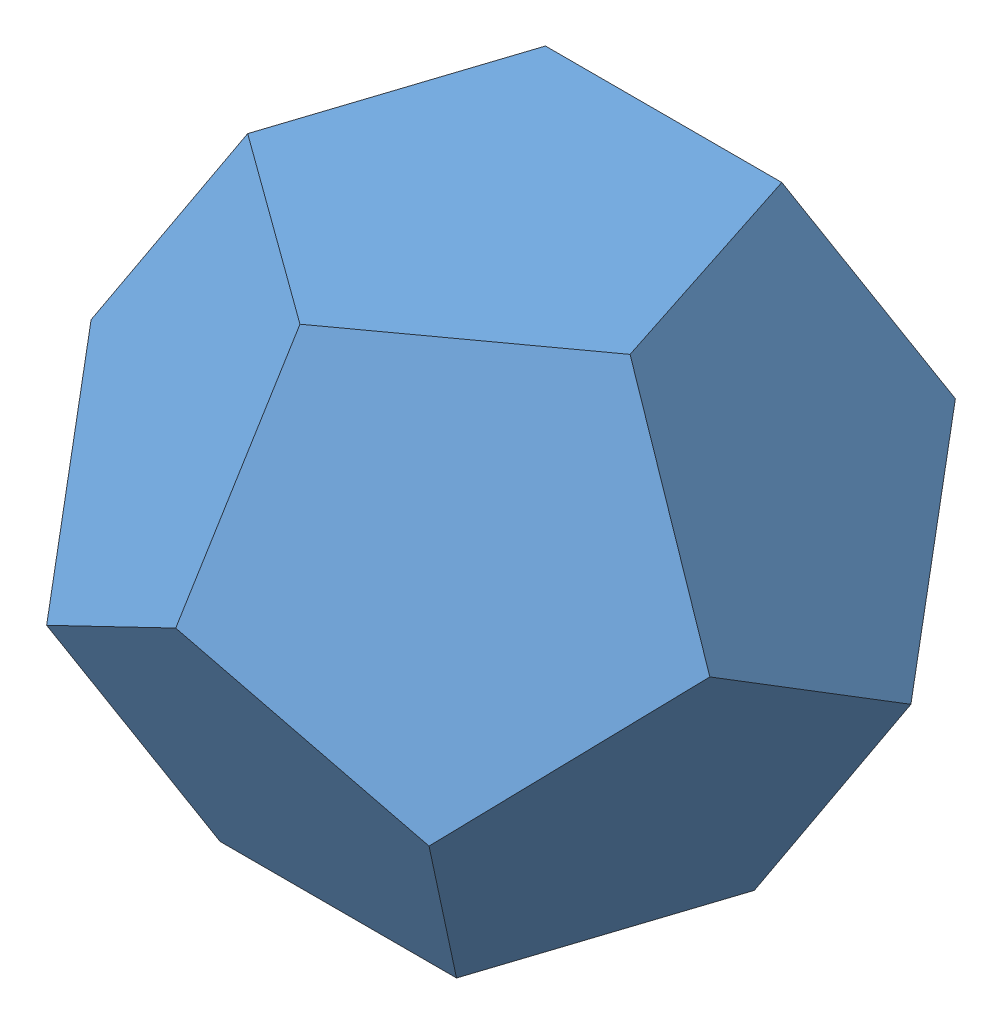
SolidWorks assembly Assem1, configuration Default. Lengths in mm.
Overall size (49.2 47.26 43.46).
6 component instances, 1 part files, 18 mates.
Components (placement in the parent):
- 2 Pyramid-1: 2 Pyramid [Default] at (0 -14.1417 0) size (26.9 17.48 24.94)
- 2 Pyramid-2: 2 Pyramid [Default] at (7.4347 -6.3243 -10.233) x (-0.5 0.525731 -0.688191) z (0.688191 0.723607 0.052786) size (26.9 17.48 24.94)
- 2 Pyramid-3: 2 Pyramid [Default] at (0 -6.3243 12.6487) x (-0.309017 0.850651 0.425325) z (-0.951057 -0.276393 -0.138197) size (26.9 17.48 24.94)
- 2 Pyramid-4: 2 Pyramid [Default] at (-12.0296 6.3243 -3.9087) x (0.309017 0.850651 0.425325) z (0.425325 0.276393 -0.861803) size (26.9 17.48 24.94)
- 2 Pyramid-5: 2 Pyramid [Default] at (-7.4347 -6.3243 -10.233) x (-0.5 -0.525731 0.688191) z (-0.688191 0.723607 0.052786) size (26.9 17.48 24.94)
- 2 Pyramid-6: 2 Pyramid [Default] at (7.4347 6.3243 10.233) x (0.809017 0 -0.587785) z (-0.262866 0.894427 -0.361803) size (26.9 17.48 24.94)
Mates (geometry in assembly coordinates):
- Coincident1: coincident: point of 2 Pyramid-1
- Parallel1: parallel aligned: plane of 2 Pyramid-1 through (0 -14.1417 0) normal (0 1 0)
- Coincident3: coincident aligned: plane of 2 Pyramid-1 through (0 -14.1417 0) normal (0 0 1)
- Coincident5: coincident anti-aligned: plane of 2 Pyramid-1 through (10.2745 -14.1417 -3.3384) normal (-0.309017 0 -0.951057); plane of 2 Pyramid-2 through (10.2745 -14.1417 -3.3384) normal (0.309017 0 0.951057)
- Coincident6: coincident anti-aligned: plane of 2 Pyramid-1 through (10.2745 -14.1417 -3.3384) normal (0.5 0.525731 -0.688191); plane of 2 Pyramid-2 through (0 -14.1417 -10.8033) normal (-0.5 -0.525731 0.688191)
- Coincident7: coincident: point of 2 Pyramid-1; point of 2 Pyramid-2
- Coincident8: coincident anti-aligned: plane of 2 Pyramid-1 through (-6.35 -14.1417 8.74) normal (0 0.525731 0.850651); plane of 2 Pyramid-3 through (6.35 -14.1417 8.74) normal (0 -0.525731 -0.850651)
- Coincident9: coincident anti-aligned: plane of 2 Pyramid-1 through (10.2745 -3.3384 14.1417) normal (-0.809017 0 0.587785); plane of 2 Pyramid-3 through (10.2745 -3.3384 14.1417) normal (0.809017 0 -0.587785)
- Coincident10: coincident: unknown of 2 Pyramid-3
- Coincident11: coincident anti-aligned: plane of 2 Pyramid-2 through (-6.35 14.1417 -8.74) normal (0 0.525731 0.850651); plane of 2 Pyramid-4 through (6.35 14.1417 -8.74) normal (0 -0.525731 -0.850651)
- Coincident12: coincident anti-aligned: plane of 2 Pyramid-2 through (-10.2745 3.3384 -14.1417) normal (-0.809017 0 0.587785); plane of 2 Pyramid-4 through (-10.2745 3.3384 -14.1417) normal (0.809017 0 -0.587785)
- Coincident13: coincident: unknown of 2 Pyramid-4
- Coincident14: coincident anti-aligned: plane of 2 Pyramid-1 through (-10.2745 -14.1417 -3.3384) normal (-0.809017 0.525731 0.262866); plane of 2 Pyramid-5 through (-10.2745 -14.1417 -3.3384) normal (0.809017 -0.525731 -0.262866)
- Coincident15: coincident anti-aligned: plane of 2 Pyramid-1 through (0 -14.1417 -10.8033) normal (-0.5 0.525731 -0.688191); plane of 2 Pyramid-5 through (-10.2745 -14.1417 -3.3384) normal (0.5 -0.525731 0.688191)
- Coincident16: coincident: unknown of 2 Pyramid-5
- Coincident18: coincident anti-aligned: plane of 2 Pyramid-1 through (16.6245 3.3384 5.4016) normal (-0.309017 0.850651 0.425325); plane of 2 Pyramid-6 through (16.6245 3.3384 5.4016) normal (0.309017 -0.850651 -0.425325)
- Coincident19: coincident anti-aligned: plane of 2 Pyramid-1 through (16.6245 -3.3384 -5.4016) normal (0 0.850651 -0.525731); plane of 2 Pyramid-6 through (16.6245 3.3384 5.4016) normal (0 -0.850651 0.525731)
- Coincident20: coincident: unknown of 2 Pyramid-6
